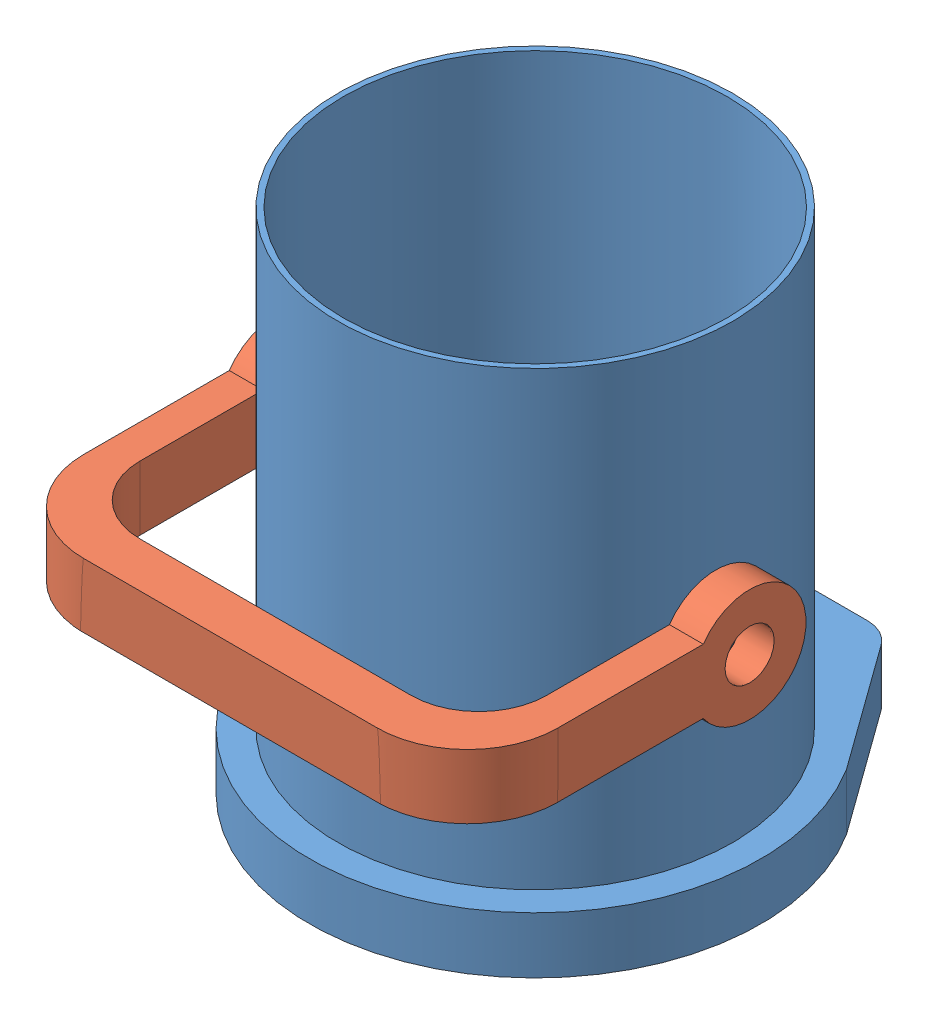
SolidWorks assembly ПылесосСБ, configuration По умолчанию. Lengths in mm.
Overall size (420 450 500.07).
2 component instances, 2 part files, 3 mates.
Components (placement in the parent):
- Керхер-1: Керхер [По умолчанию] at origin size (400 450 430)
- Ручка-1: Ручка [По умолчанию] at (0 221.7244 -30.0196) x (1 0 0) z (0 -1 0.000915) size (420 300 100)
Mates (geometry in assembly coordinates):
- Расстояние1: distance = 5 mm: plane of Ручка-1 through (-180 221.9074 169.9803) normal (1 0 0); cylinder of Керхер-1 through (0 400 0) axis (0 -1 0) radius 175
- Расстояние3: distance = 500 mm: plane of Ручка-1 through (-210 143.5292 270) normal (0 0 1); plane of Керхер-1 through (-64.6743 -50 -230) normal (0 0 -1)
- Расстояние4: distance = 143.5292 mm: line of Ручка-1 through (-132.8871 143.5292 270) axis (1 0 0); plane of Керхер-1 through (0 0 0) normal (0 1 0)
